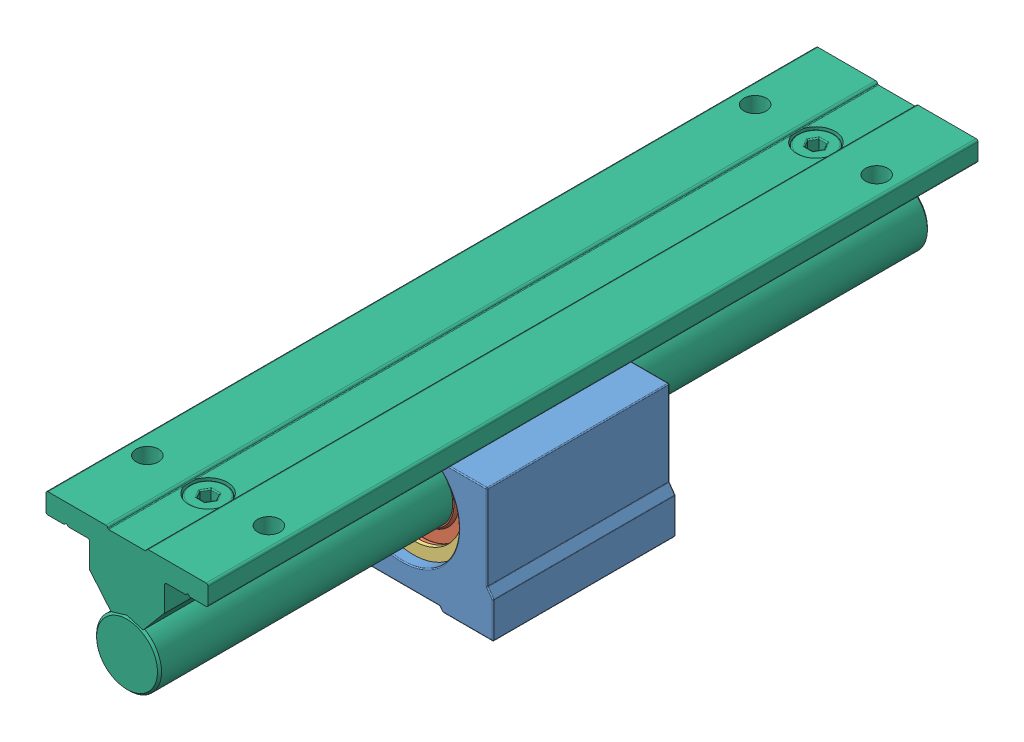
SolidWorks assembly SBR16UU, configuration По умолчанию. Lengths in mm.
Overall size (45 45 190).
7 component instances, 6 part files, 11 mates.
Components (placement in the parent):
- Корпус SBR16UU-1: Корпус SBR16UU [По умолчанию] at origin size (45 32 45)
- Подшипник LM16UUOP-2: Подшипник LM16UUOP [По умолчанию] x (-1 0 0) z (0 0 1) size (28 24.5 37.03)
- Стопорное кольцо-1: Стопорное кольцо [По умолчанию] at (0 0 19.75) size (31 24.66 1)
- Стопорное кольцо-2: Стопорное кольцо [По умолчанию] at (0 0 -18.75) size (31 24.66 1)
- Стопорный винт М4х2,5-1: Стопорный винт М4х2,5 [По умолчанию] at (0 -19 0) x (0 1 0) z (1 0 0) size (2.5 4 4)
- Стопорный винт М6х6-1: Стопорный винт М6х6 [По умолчанию] at (-21 -2 0) size (6 6 6)
- SBR16 190L N=20-1: SBR16 190L N=20 [По умолчанию] at (0 0 -1354.6334) x (0 0 1) z (1 0 0) size (190 33 40)
Mates (geometry in assembly coordinates):
- Концентричный1: concentric anti-aligned: cylinder of Корпус SBR16UU-1 through (0 0 22.5) axis (0 0 -1) radius 14; cylinder of Стопорное кольцо-1 through (0 0 18.75) axis (0 0 1) radius 15.5
- Совпадение1: coincident anti-aligned: circle of Корпус SBR16UU-1; plane of Стопорное кольцо-1 through (-5.534 3.25 19.75) normal (0 0 1)
- Концентричный2: concentric anti-aligned: cylinder of Корпус SBR16UU-1 through (0 0 22.5) axis (0 0 -1) radius 14; cylinder of Стопорное кольцо-2 through (0 0 -19.75) axis (0 0 1) radius 15.5
- Совпадение2: coincident aligned: circle of Корпус SBR16UU-1; plane of Стопорное кольцо-2 through (-5.534 3.25 -19.75) normal (0 0 -1)
- Совпадение3: coincident aligned: plane of Корпус SBR16UU-1 through (-21 -9 -22.5) normal (-1 0 0); plane of Стопорный винт М6х6-1 through (-21 -2 0) normal (-1 0 0)
- Концентричный3: concentric aligned: cylinder of Корпус SBR16UU-1 through (-21 -2 0) axis (-1 0 0) radius 2.5; cylinder of Стопорный винт М6х6-1 through (-15 -2 0) axis (-1 0 0) radius 3
- Концентричный5: concentric aligned: cylinder of Корпус SBR16UU-1 through (0 -19 0) axis (0 -1 0) radius 1.65; cylinder of Стопорный винт М4х2,5-1 through (0 -16.5 0) axis (0 -1 0) radius 2
- Совпадение4: coincident aligned: plane of Корпус SBR16UU-1 through (9.25 -19 -22.5) normal (0 -1 0); plane of Стопорный винт М4х2,5-1 through (0 -19 0) normal (0 -1 0)
- Концентричный7: concentric: cylinder of Корпус SBR16UU-1 through (0 0 22.5) axis (0 0 -1) radius 14; cylinder of Подшипник LM16UUOP-2 through (0 0 43.3432) axis (0 0 1) radius 8
- Концентричный8: concentric anti-aligned: cylinder of Подшипник LM16UUOP-2 through (0 0 43.3432) axis (0 0 1) radius 8; cylinder of SBR16 190L N=20-1 through (0 0 145.3666) axis (0 0 -1) radius 8
- Параллельность1: parallel aligned: plane of Корпус SBR16UU-1 through (-22.5 -20 22.5) normal (0 -1 0); plane of SBR16 190L N=20-1 through (0 20 145.3666) normal (0 -1 0)
